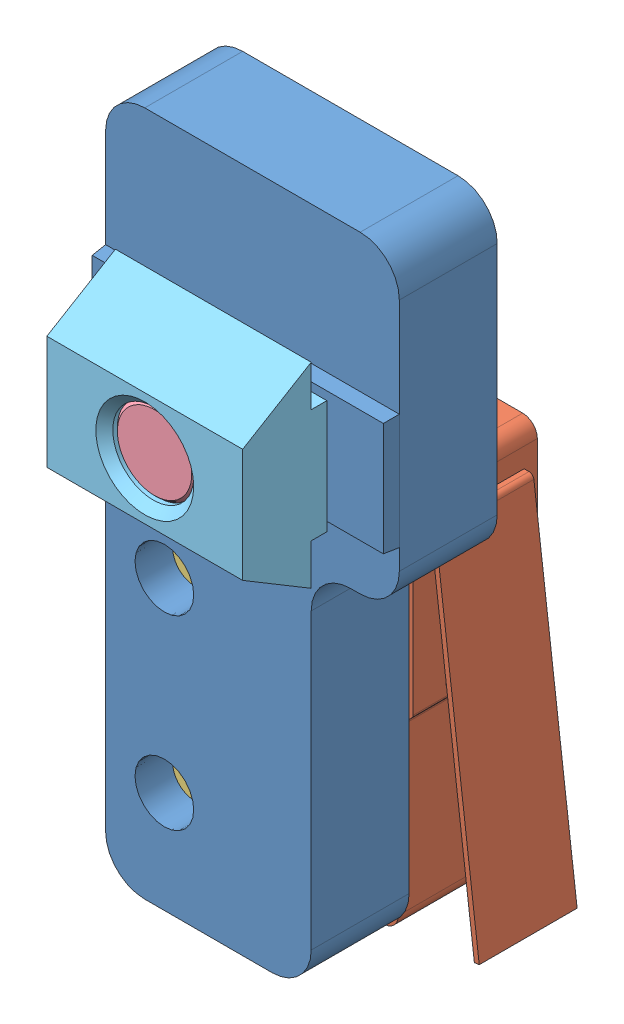
SolidWorks assembly Assem1, configuration Default. Lengths in mm.
Overall size (18.3 35.06 18.82).
6 component instances, 5 part files, 12 mates.
Components (placement in the parent):
- XY_LimitSwitch_Mount_A-1: XY_LimitSwitch_Mount_A [Default] at origin size (15 35 5.75)
- Micro Switch Button-1: Micro Switch Button [Default] at (5.4 -24.2 -3.175) x (0 0 -1) z (0 -1 0) size (6.75 16.71 19.86)
- 3mmX10mm_Buttonhead(McMaster_94500A223)-1: 3mmX10mm_Buttonhead(McMaster_94500A223) [94500A223] at (3 -20.3 -8.2) x (-0.104052 -0.994572 0) z (0 0 -1) size (5.7 5.7 11.96)
- 3mmX10mm_Buttonhead(McMaster_94500A223)-2: 3mmX10mm_Buttonhead(McMaster_94500A223) [94500A223] at (3 -29.8 -8.2) x (0.005554 -0.999985 0) z (0 0 -1) size (5.7 5.7 11.96)
- 5mmX10mm_Buttonhead(McMaster_91239A224)-1: 5mmX10mm_Buttonhead(McMaster_91239A224) [91239A224] at (7.5 -10 -2.75) x (-0.923728 -0.383049 0) z (0 0 -1) size (9.5 9.5 13.21)
- HNTTSN5-5-1: HNTTSN5-5 [Default] at (7.5 -10 6.2) x (0 0 -1) z (1 0 0) size (4.3 10 10)
Mates (geometry in assembly coordinates):
- Concentric1: concentric aligned: cylinder of XY_LimitSwitch_Mount_A-1 through (3 -20.3 5) axis (0 0 -1) radius 1.5; cylinder of Micro Switch Button-1 through (3 -20.3 0) axis (0 0 -1) radius 1.35
- Concentric2: concentric aligned: cylinder of XY_LimitSwitch_Mount_A-1 through (3 -29.8 5) axis (0 0 -1) radius 1.5; cylinder of Micro Switch Button-1 through (3 -29.8 0) axis (0 0 -1) radius 1.35
- Coincident1: coincident anti-aligned: plane of XY_LimitSwitch_Mount_A-1 through (8.5 -33 0) normal (0 0 -1); plane of Micro Switch Button-1 through (0.8 -15.4 0) normal (0 0 1)
- Concentric3: concentric aligned: cylinder of Micro Switch Button-1 through (3 -20.3 0) axis (0 0 -1) radius 1.35; cylinder of 3mmX10mm_Buttonhead(McMaster_94500A223)-1 through (3 -20.3 -8.2) axis (0 0 -1) radius 2.85
- Concentric4: concentric aligned: cylinder of Micro Switch Button-1 through (3 -29.8 0) axis (0 0 -1) radius 1.35; cylinder of 3mmX10mm_Buttonhead(McMaster_94500A223)-2 through (3 -29.8 -8.2) axis (0 0 -1) radius 2.85
- Coincident2: coincident anti-aligned: plane of Micro Switch Button-1 through (3 -20.3 -6.55) normal (0 0 -1); plane of 3mmX10mm_Buttonhead(McMaster_94500A223)-1 through (5.8345 -20.5965 -6.55) normal (0 0 1)
- Coincident3: coincident anti-aligned: plane of Micro Switch Button-1 through (3 -29.8 -6.55) normal (0 0 -1); plane of 3mmX10mm_Buttonhead(McMaster_94500A223)-2 through (5.85 -29.7842 -6.55) normal (0 0 1)
- Concentric5: concentric aligned: cylinder of XY_LimitSwitch_Mount_A-1 through (7.5 -10 5) axis (0 0 -1) radius 2.7; cylinder of 5mmX10mm_Buttonhead(McMaster_91239A224)-1 through (7.5 -10 -2.75) axis (0 0 -1) radius 4.75
- Coincident4: coincident anti-aligned: plane of XY_LimitSwitch_Mount_A-1 through (8.5 -33 0) normal (0 0 -1); plane of 5mmX10mm_Buttonhead(McMaster_91239A224)-1 through (9.3195 -14.3877 0) normal (0 0 1)
- Concentric6: concentric anti-aligned: cylinder of 5mmX10mm_Buttonhead(McMaster_91239A224)-1 through (7.5 -10 -2.75) axis (0 0 -1) radius 4.75; cylinder of HNTTSN5-5-1 through (7.5 -10 6.2) axis (0 0 1) radius 2.067
- Parallel1: parallel aligned: plane of XY_LimitSwitch_Mount_A-1 through (0 -2 5) normal (-1 0 0); plane of HNTTSN5-5-1 through (2.5 -10 6.2) normal (-1 0 0)
- Distance1: distance = 2 mm anti-aligned: plane of HNTTSN5-5-1 through (12.5 -7.1 7) normal (0 0 -1); plane of XY_LimitSwitch_Mount_A-1 through (8.5 -33 5) normal (0 0 1)
